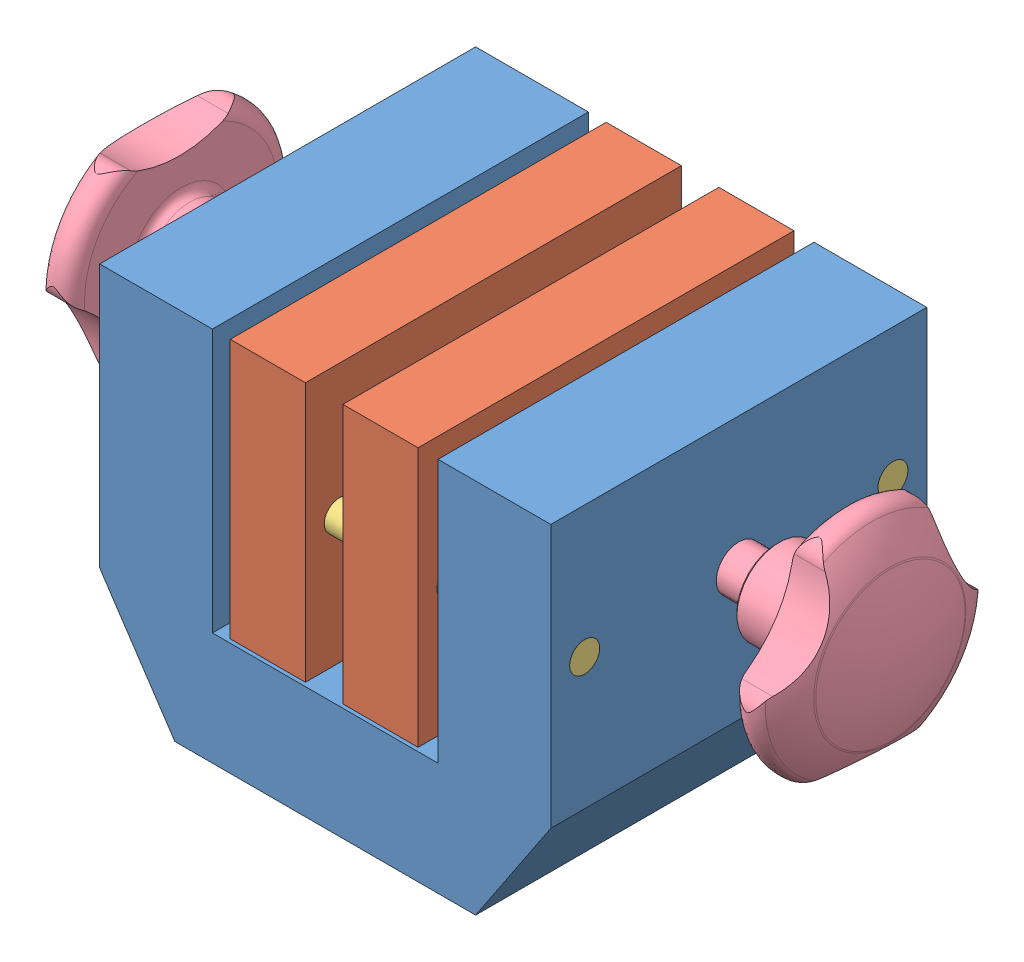
SolidWorks assembly mount, configuration Domyślna. Lengths in mm.
Overall size (207.96 105.91 100).
7 component instances, 4 part files, 25 mates.
Components (placement in the parent):
- body-1: body [Domyślna] at (-6.687 13.6734 100) size (120 100 100)
- clamp-1: clamp [Domyślna] at (-11.9514 28.6734 150) x (0 0 1) z (-1 0 0) size (100 69 20)
- clamp-2: clamp [Domyślna] at (-1.992 28.6734 150) x (0 0 -1) z (1 0 0) size (100 69 20)
- shaft_specimen_mount-1: shaft_specimen_mount [Domyślna] at (-66.687 28.6734 109) size (120 8 8)
- shaft_specimen_mount-2: shaft_specimen_mount [Domyślna] at (-66.687 28.6734 191) size (120 8 8)
- Three-lobe handwheel VTT.60-p-M12x60.stp-3: Three-lobe handwheel VTT.60-p-M12x60.stp [Domyślna] at (3.008 28.6734 150) x (1 0 0) z (0 0.045114 0.998982) size (94 57.21 59.57)
- Three-lobe handwheel VTT.60-p-M12x60.stp-4: Three-lobe handwheel VTT.60-p-M12x60.stp [Domyślna] at (-16.9514 28.6734 150) x (-1 0 0) z (0 -0.860616 -0.509254) size (94 57.21 59.57)
Mates (geometry in assembly coordinates):
- Concentric1: concentric anti-aligned: cylinder of body-1 through (-66.687 28.6734 109) axis (1 0 0) radius 4; cylinder of shaft-2 through (53.313 28.6734 109) axis (-1 0 0) radius 4
- Coincident1: coincident aligned: plane of body-1 through (53.313 -36.3266 200) normal (1 0 0); plane of shaft-2 through (53.313 28.6734 109) normal (1 0 0)
- Concentric2: concentric anti-aligned: cylinder of body-1 through (-66.687 28.6734 191) axis (1 0 0) radius 4; cylinder of shaft-1 through (53.313 28.6734 191) axis (-1 0 0) radius 4
- Coincident2: coincident aligned: plane of body-1 through (-66.687 -36.3266 200) normal (-1 0 0); plane of shaft-1 through (-66.687 28.6734 191) normal (-1 0 0)
- Concentric3: concentric anti-aligned: cylinder of shaft-1 through (53.313 28.6734 191) axis (-1 0 0) radius 4; cylinder of clamp-1 through (-32.6539 28.6734 191) axis (1 0 0) radius 4.1
- Concentric4: concentric anti-aligned: cylinder of shaft-2 through (53.313 28.6734 109) axis (-1 0 0) radius 4; cylinder of clamp-1 through (-32.6539 28.6734 109) axis (1 0 0) radius 4.1
- Concentric5: concentric aligned: cylinder of shaft-1 through (53.313 28.6734 191) axis (-1 0 0) radius 4; cylinder of clamp-2 through (20.8314 28.6734 191) axis (-1 0 0) radius 4.1
- Concentric6: concentric aligned: cylinder of shaft-2 through (53.313 28.6734 109) axis (-1 0 0) radius 4; cylinder of clamp-2 through (20.8314 28.6734 109) axis (-1 0 0) radius 4.1
- Coincident3: coincident aligned: plane of shaft_specimen_mount-1 through (-66.687 28.6734 109) normal (-1 0 0); plane of shaft_specimen_mount-2 through (-66.687 28.6734 191) normal (-1 0 0)
- Coincident4: coincident aligned: plane of body-1 through (-66.687 -36.3266 200) normal (-1 0 0); plane of shaft_specimen_mount-1 through (-66.687 28.6734 109) normal (-1 0 0)
- Concentric7: concentric anti-aligned: cylinder of body-1 through (-66.687 28.6734 109) axis (1 0 0) radius 4; cylinder of shaft_specimen_mount-1 through (53.313 28.6734 109) axis (-1 0 0) radius 4
- Concentric8: concentric anti-aligned: cylinder of body-1 through (-66.687 28.6734 191) axis (1 0 0) radius 4; cylinder of shaft_specimen_mount-2 through (53.313 28.6734 191) axis (-1 0 0) radius 4
- Concentric11: concentric aligned: cylinder of clamp-2 through (18.008 28.6734 109) axis (-1 0 0) radius 4; cylinder of shaft_specimen_mount-1 through (53.313 28.6734 109) axis (-1 0 0) radius 4
- Concentric12: concentric aligned: cylinder of clamp-2 through (18.008 28.6734 191) axis (-1 0 0) radius 4; cylinder of shaft_specimen_mount-2 through (53.313 28.6734 191) axis (-1 0 0) radius 4
- Concentric13: concentric anti-aligned: cylinder of clamp-1 through (-31.9514 28.6734 109) axis (1 0 0) radius 4; cylinder of shaft_specimen_mount-1 through (53.313 28.6734 109) axis (-1 0 0) radius 4
- Concentric14: concentric anti-aligned: cylinder of clamp-1 through (-31.9514 28.6734 191) axis (1 0 0) radius 4; cylinder of shaft_specimen_mount-2 through (53.313 28.6734 191) axis (-1 0 0) radius 4
- Concentric15: concentric anti-aligned: cylinder of body-1 through (-66.687 28.6734 150) axis (1 0 0) radius 6; cylinder of Three-lobe handwheel VTT.60-p-M12x60.stp-2 through (-76.9514 28.6734 150) axis (-1 0 0) radius 6
- Concentric16: concentric aligned: cylinder of body-1 through (-66.687 28.6734 150) axis (1 0 0) radius 6; cylinder of Three-lobe handwheel VTT.60-p-M12x60.stp-1 through (62.5213 28.6734 150) axis (1 0 0) radius 6
- Coincident5: coincident anti-aligned: plane of clamp-1 through (-16.9514 28.6734 150) normal (-1 0 0); plane of Three-lobe handwheel VTT.60-p-M12x60.stp-2 through (-16.9514 28.6734 150) normal (1 0 0)
- Coincident6: coincident anti-aligned: plane of clamp-2 through (3.008 28.6734 150) normal (1 0 0); plane of Three-lobe handwheel VTT.60-p-M12x60.stp-1 through (2.5213 28.6734 150) normal (-1 0 0)
- Coincident7: coincident: plane of clamp-1 through (-16.9514 28.6734 150) normal (-1 0 0); plane of Three-lobe handwheel VTT.60-p-M12x60.stp-4 through (-16.9514 28.6734 150) normal (1 0 0)
- Concentric18: concentric aligned: cylinder of body-1 through (-66.687 28.6734 150) axis (1 0 0) radius 6; cylinder of Three-lobe handwheel VTT.60-p-M12x60.stp-3 through (63.008 28.6734 150) axis (1 0 0) radius 6
- Coincident8: coincident anti-aligned: plane of clamp-2 through (3.008 28.6734 150) normal (1 0 0); plane of Three-lobe handwheel VTT.60-p-M12x60.stp-3 through (3.008 28.6734 150) normal (-1 0 0)
- Concentric19: concentric anti-aligned: cylinder of body-1 through (-66.687 28.6734 150) axis (1 0 0) radius 6; cylinder of Three-lobe handwheel VTT.60-p-M12x60.stp-4 through (-76.9514 28.6734 150) axis (-1 0 0) radius 6
- Coincident9: coincident anti-aligned: plane of clamp-1 through (-16.9514 28.6734 150) normal (-1 0 0); plane of Three-lobe handwheel VTT.60-p-M12x60.stp-4 through (-16.9514 28.6734 150) normal (1 0 0)
